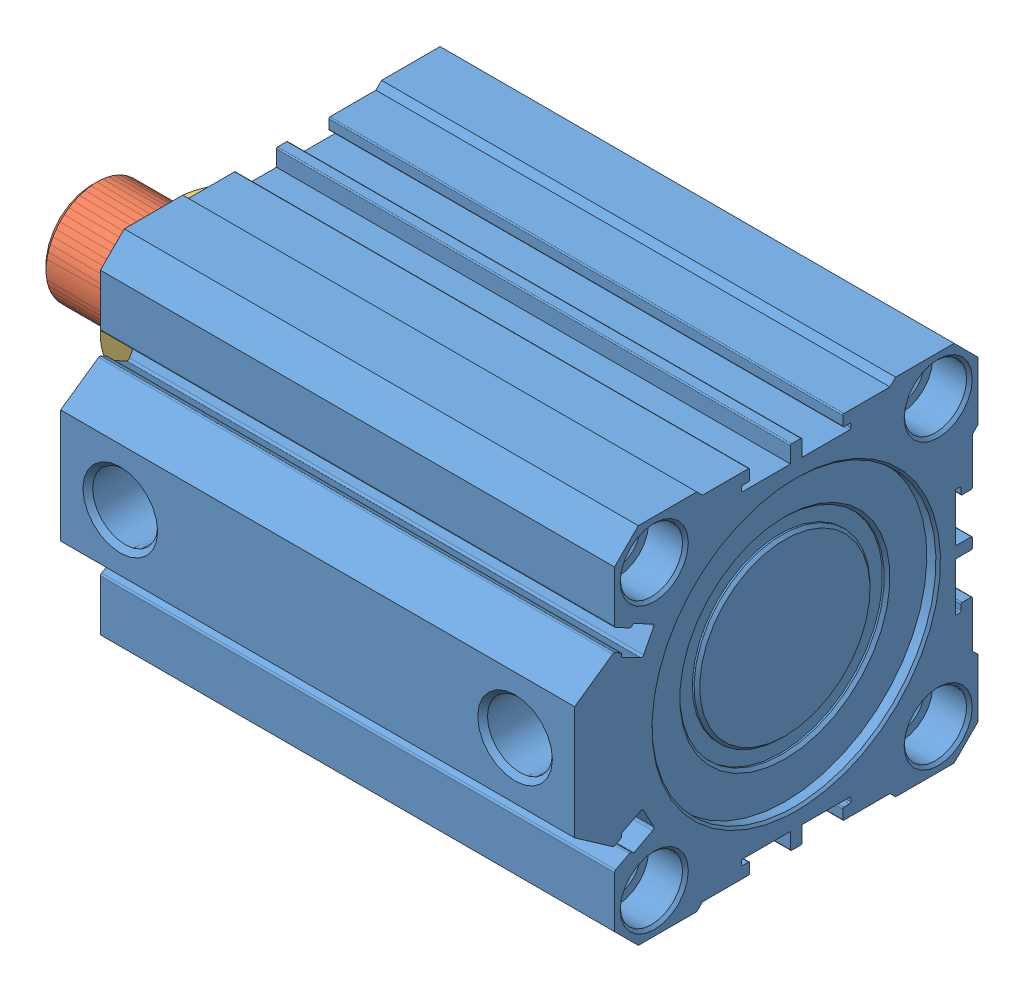
SolidWorks assembly 00-ACQ50x50SB(0)+(), configuration 默认. Lengths in mm.
Overall size (124 64 71).
3 component instances, 3 part files, 5 mates.
Components (placement in the parent):
- 00-ACQS-50x5050_b-1: 00-ACQS-50x5050_b [默认] x (1 0 0) z (0 -1 0) size (90.5 71 64)
- 00-ACQS-50x50-B_50r-1: 00-ACQS-50x50-B_50r [默认] at origin size (115 50 50)
- 00-ACQ 50_Nut-1: 00-ACQ 50_Nut [默认] at (-7.5 0 0) x (-1 0 0) z (0 0.341797 -0.939774) size (11 34.29 27)
Mates (geometry in assembly coordinates):
- 重合1: coincident anti-aligned: line of 00-ACQS-50x5050_b-1 through (-80.9 0 0) axis (1 0 0); line of 00-ACQS-50x50-B_50r-1 through (161.8 80.9 0) axis (0 -1 0)
- 角度2: planar angle = 1.570796 rad anti-aligned: plane of 00-ACQS-50x50-B_50r-1 through (0 0 0) normal (0 0 -1); plane of 00-ACQS-50x5050_b-1
- LimitDistance1: limit distance = 33.5 mm aligned: plane of 00-ACQS-50x50-B_50r-1 through (-33.5 0 0) normal (-1 0 0); plane of 00-ACQS-50x5050_b-1 through (0 -8.4 -30.8) normal (-1 0 0)
- 距离2: distance = 15 mm aligned: plane of 00-ACQS-50x50-B_50r-1 through (-33.5 0 0) normal (-1 0 0); plane of 00-ACQ 50_Nut-1 through (-18.5 12.6869 4.6143) normal (-1 0 0)
- 同心1: concentric anti-aligned: cylinder of 00-ACQS-50x50-B_50r-1 through (0 0 0) axis (-1 0 0) radius 9; cylinder of 00-ACQ 50_Nut-1 through (-18.5 0 0) axis (1 0 0) radius 8.188
